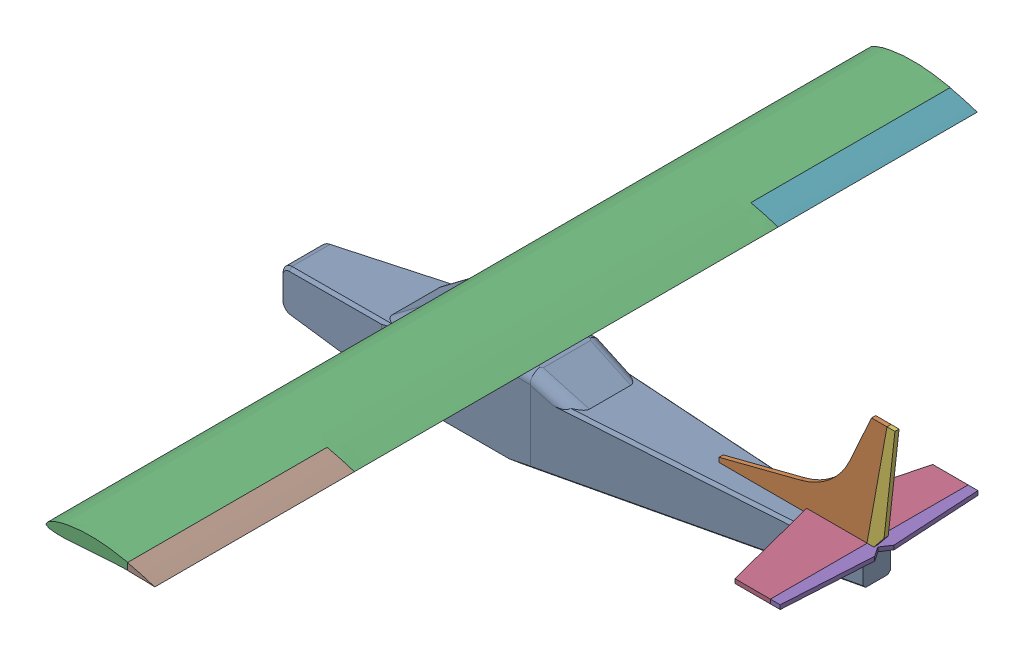
SolidWorks assembly Assem2, configuration Default. Lengths in mm.
Overall size (2158.14 667.22 2980.89).
7 component instances, 7 part files, 15 mates.
Components (placement in the parent):
- Main body-1: Main body [Default] at (693.788 928.3305 1753.2994) size (2084.84 310.62 250)
- Fin-1: Fin [Default] at (1408.9264 1179.5459 1745.7994) size (608.46 416 15)
- Airfoil-wing-1: Airfoil-wing [Default] at (216.3202 1249.856 1753.2994) size (395.24 54.85 2980)
- Stab-1: Stab [Default] at (1708.971 1179.5459 1825.2459) size (220.99 15 716.7)
- elevator-1: elevator [Default] at (1708.971 1179.5459 1753.2994) size (54.57 15 716.7)
- Rudder-1: Rudder [Default] at (1408.9264 1179.5459 1745.7994) size (103.98 416 15)
- Ailerons-1: Ailerons [Default] at (415.8165 1292.3215 1754.1932) size (98.85 27.57 2980)
Mates (geometry in assembly coordinates):
- Coincident1: coincident anti-aligned: plane of Main body-1 through (770.2373 1179.5459 1878.2994) normal (0 1 0); plane of Fin-1 through (1172.197 1179.5459 1760.7994) normal (0 -1 0)
- Width1: width aligned: plane of Main body-1 through (1736.204 928.3305 1803.2994) normal (0.066274 0 0.997801); plane of Fin-1 through (607.0288 928.3305 1628.2994) normal (0.066274 0 -0.997801); plane of Main body-1 through (1400.0171 1533.2114 1745.7994) normal (0 0 -1); plane of Fin-1 through (1400.0171 1533.2114 1760.7994) normal (0 0 1)
- Coincident2: coincident anti-aligned: plane of Fin-1 through (1705.5235 1179.5459 1745.7994) normal (0.984077 -0.177744 0); plane of Rudder-1 through (1705.5235 1179.5459 1760.7994) normal (-0.984077 0.177744 0)
- Coincident3: coincident anti-aligned: plane of Main body-1 through (770.2373 1179.5459 1878.2994) normal (0 1 0); plane of Rudder-1 through (1720.8712 1179.5459 1760.7994) normal (0 -1 0)
- Coincident4: coincident aligned: plane of Fin-1 through (1400.0171 1533.2114 1760.7994) normal (0 0 1); plane of Rudder-1 through (1408.9264 1179.5459 1760.7994) normal (0 0 1)
- Coincident5: coincident anti-aligned: plane of Main body-1 through (770.2373 1179.5459 1878.2994) normal (0 1 0); plane of Stab-1 through (1708.971 1179.5459 1825.2459) normal (0 -1 0)
- Width2: width anti-aligned: plane of Main body-1 through (1736.204 928.3305 1803.2994) normal (0.066274 0 0.997801); plane of Stab-1 through (607.0288 928.3305 1628.2994) normal (0.066274 0 -0.997801); plane of Main body-1 through (1708.971 1194.5459 2111.6494) normal (0 0 1); plane of Stab-1 through (1580.5992 1194.5459 1394.9494) normal (0 0 -1)
- Coincident6: coincident anti-aligned: plane of Stab-1 through (1708.971 1194.5459 1394.9494) normal (1 0 0); plane of elevator-1 through (1708.971 1194.5459 1394.9494) normal (-1 0 0)
- Coincident7: coincident aligned: plane of Stab-1 through (1708.971 1194.5459 2111.6494) normal (0 0 1); plane of elevator-1 through (1708.971 1194.5459 2111.6494) normal (0 0 1)
- Coincident8: coincident aligned: plane of Stab-1 through (1708.971 1194.5459 1825.2459) normal (0 1 0); plane of elevator-1 through (1708.971 1194.5459 1753.2994) normal (0 1 0)
- Width3: width anti-aligned: plane of Main body-1 through (693.788 928.3305 1878.2994) normal (0 0 1); plane of Airfoil-wing-1 through (693.788 928.3305 1628.2994) normal (0 0 -1); plane of Main body-1 through (219.4414 1255.3943 263.2994) normal (0 0 -1); plane of Airfoil-wing-1 through (219.4414 1255.3943 3243.2994) normal (0 0 1)
- Lock1: lock: unknown of Main body-1; unknown of Airfoil-wing-1
- Tangent1: tangent: curve of Airfoil-wing-1; curve of Ailerons-1
- Parallel3: parallel aligned: line of Main body-1 through (1736.204 1179.5459 1793.2773) axis (0 0 -1); line of Rudder-1 through (1770.1598 1240.0355 1760.7994) axis (0 0 -1)
- Lock2: lock: unknown of Stab-1; unknown of Rudder-1
